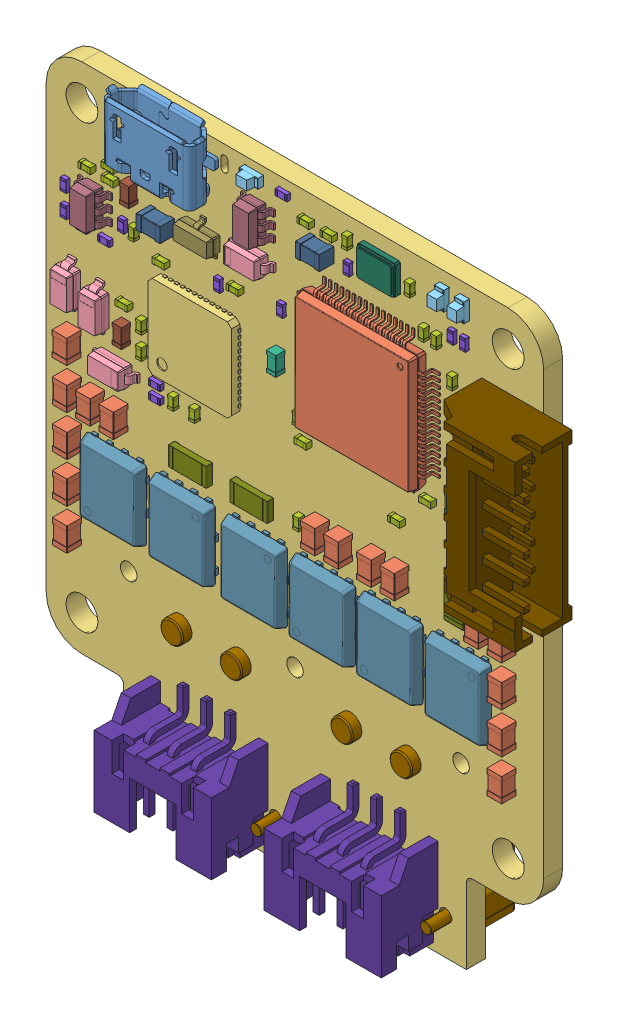
SolidWorks assembly Daedalus, configuration Default. Lengths in mm.
Overall size (44.43 51.31 11.63).
180 component instances, 21 part files, 0 mates.
Components (placement in the parent):
- Daedalus.step-1: Daedalus.step [Default] at origin size (44.43 51.31 11.63)
  - molex_0473460001.step-1: molex_0473460001.step [Default] at (133.8224 -76.8655 1.65) x (-1 0 0) z (0 1 0) size (7.98 2.76 5.43)
    - COMPOUND.step-1: COMPOUND.step [Default] at origin size (7.98 2.76 5.43)
  - LQFP-64_10x10mm_P0.5mm.step-1: LQFP-64_10x10mm_P0.5mm.step [Default] at (150.2843 -86.8057 1.65) x (0 -1 0) z (0 0 1) size (12 12 1.5)
    - SOLID.step-1: SOLID.step [Default] at origin size (12 12 1.5)
  - QFN127P600-8N.step-1: QFN127P600-8N.step [Default] at (135.871 -91.0039 1.65) x (0 1 0) z (0 0 1) size (7.15 7.15 0.75)
    - COMPOUND-0.step-1: COMPOUND-0.step [Default] at origin size (7.15 7.15 0.75)
  - D_SOD-123.step-1: D_SOD-123.step [Default] at (140.4976 -82.2096 1.65) size (3.8 1.6 1.25)
    - SOLID-1.step-1: SOLID-1.step [Default] at origin size (3.8 1.6 1.25)
  - LED_0603_1608Metric.step-1: LED_0603_1608Metric.step [Default] at (156.6516 -77.1197 1.65) x (0 1 0) z (0 0 1) size (1.6 0.8 1.1)
    - SOLID-2.step-1: SOLID-2.step [Default] at origin size (1.6 0.8 1.1)
  - C_0603_1608Metric.step-1: C_0603_1608Metric.step [Default] at (157.7975 -91.44 1.65) x (0 -1 0) z (0 0 1) size (1.6 0.8 0.8)
    - SOLID-3.step-1: SOLID-3.step [Default] at origin size (1.6 0.8 0.8)
  - C_0402_1005Metric.step-1: C_0402_1005Metric.step [Default] at (130.6322 -85.3769 1.65) x (0 -1 0) z (0 0 1) size (1 0.5 0.5)
    - SOLID-4.step-1: SOLID-4.step [Default] at origin size (1 0.5 0.5)
  - C_0402_1005Metric.step-2: C_0402_1005Metric.step [Default] at (126.6952 -82.5398 1.65) x (-1 0 0) z (0 0 1) size (1 0.5 0.5)
    - SOLID-4.step-1: SOLID-4.step [Default] at origin size (1 0.5 0.5)
  - R_0402_1005Metric.step-1: R_0402_1005Metric.step [Default] at (143.0426 -84.8411 1.65) x (0 -1 0) z (0 0 1) size (1 0.5 0.35)
    - SOLID-5.step-1: SOLID-5.step [Default] at origin size (1 0.5 0.35)
  - C_0402_1005Metric.step-3: C_0402_1005Metric.step [Default] at (147.0948 -77.337 1.65) size (1 0.5 0.5)
    - SOLID-4.step-1: SOLID-4.step [Default] at origin size (1 0.5 0.5)
  - Amass_XT30PW-M_pcb_solder.step-1: Amass_XT30PW-M_pcb_solder.step [Default] at (151.1541 -116.5924 -2.59) x (-1 0 0) z (0 0 -1) size (13.3 13.95 8.49)
    - SOLID-6.step-1: SOLID-6.step [Default] at origin size (13.3 13.95 8.49)
  - Amass_XT30PW-M_pcb_solder.step-2: Amass_XT30PW-M_pcb_solder.step [Default] at (136.8031 -116.5924 -2.59) x (-1 0 0) z (0 0 -1) size (13.3 13.95 8.49)
    - SOLID-6.step-1: SOLID-6.step [Default] at origin size (13.3 13.95 8.49)
  - R_0402_1005Metric.step-2: R_0402_1005Metric.step [Default] at (132.4508 -96.6368 1.65) x (-1 0 0) z (0 0 1) size (1 0.5 0.35)
    - SOLID-5.step-1: SOLID-5.step [Default] at origin size (1 0.5 0.35)
  - C_0402_1005Metric.step-4: C_0402_1005Metric.step [Default] at (128.6307 -82.55 1.65) size (1 0.5 0.5)
    - SOLID-4.step-1: SOLID-4.step [Default] at origin size (1 0.5 0.5)
  - C_0402_1005Metric.step-5: C_0402_1005Metric.step [Default] at (128.6307 -81.5442 1.65) size (1 0.5 0.5)
    - SOLID-4.step-1: SOLID-4.step [Default] at origin size (1 0.5 0.5)
  - C_0402_1005Metric.step-6: C_0402_1005Metric.step [Default] at (156.1898 -80.4962 1.65) x (0 -1 0) z (0 0 1) size (1 0.5 0.5)
    - SOLID-4.step-1: SOLID-4.step [Default] at origin size (1 0.5 0.5)
  - C_0402_1005Metric.step-7: C_0402_1005Metric.step [Default] at (157.5233 -82.8282 1.65) x (0 1 0) z (0 0 1) size (1 0.5 0.5)
    - SOLID-4.step-1: SOLID-4.step [Default] at origin size (1 0.5 0.5)
  - C_0402_1005Metric.step-8: C_0402_1005Metric.step [Default] at (144.9198 -93.5904 1.65) size (1 0.5 0.5)
    - SOLID-4.step-1: SOLID-4.step [Default] at origin size (1 0.5 0.5)
  - C_0402_1005Metric.step-9: C_0402_1005Metric.step [Default] at (144.5058 -91.9897 1.65) x (0 1 0) z (0 0 1) size (1 0.5 0.5)
    - SOLID-4.step-1: SOLID-4.step [Default] at origin size (1 0.5 0.5)
  - C_0402_1005Metric.step-10: C_0402_1005Metric.step [Default] at (155.1103 -80.4787 1.65) x (0 -1 0) z (0 0 1) size (1 0.5 0.5)
    - SOLID-4.step-1: SOLID-4.step [Default] at origin size (1 0.5 0.5)
  - C_0402_1005Metric.step-11: C_0402_1005Metric.step [Default] at (155.4448 -92.6154 1.65) x (-1 0 0) z (0 0 1) size (1 0.5 0.5)
    - SOLID-4.step-1: SOLID-4.step [Default] at origin size (1 0.5 0.5)
  - C_0402_1005Metric.step-12: C_0402_1005Metric.step [Default] at (145.1598 -77.337 1.65) size (1 0.5 0.5)
    - SOLID-4.step-1: SOLID-4.step [Default] at origin size (1 0.5 0.5)
  - C_0402_1005Metric.step-13: C_0402_1005Metric.step [Default] at (131.2824 -93.787 1.65) x (0 1 0) z (0 0 1) size (1 0.5 0.5)
    - SOLID-4.step-1: SOLID-4.step [Default] at origin size (1 0.5 0.5)
  - C_0402_1005Metric.step-14: C_0402_1005Metric.step [Default] at (133.9799 -96.078 1.65) x (0 1 0) z (0 0 1) size (1 0.5 0.5)
    - SOLID-4.step-1: SOLID-4.step [Default] at origin size (1 0.5 0.5)
  - C_0402_1005Metric.step-15: C_0402_1005Metric.step [Default] at (132.9334 -86.4108 1.65) x (-1 0 0) z (0 0 1) size (1 0.5 0.5)
    - SOLID-4.step-1: SOLID-4.step [Default] at origin size (1 0.5 0.5)
  - C_0402_1005Metric.step-16: C_0402_1005Metric.step [Default] at (131.2824 -91.8566 1.65) x (0 -1 0) z (0 0 1) size (1 0.5 0.5)
    - SOLID-4.step-1: SOLID-4.step [Default] at origin size (1 0.5 0.5)
  - C_0603_1608Metric.step-2: C_0603_1608Metric.step [Default] at (142.7886 -88.6663 1.65) x (0 1 0) z (0 0 1) size (1.6 0.8 0.8)
    - SOLID-3.step-1: SOLID-3.step [Default] at origin size (1.6 0.8 0.8)
  - C_0402_1005Metric.step-17: C_0402_1005Metric.step [Default] at (135.7681 -96.0703 1.65) x (0 -1 0) z (0 0 1) size (1 0.5 0.5)
    - SOLID-4.step-1: SOLID-4.step [Default] at origin size (1 0.5 0.5)
  - C_0402_1005Metric.step-18: C_0402_1005Metric.step [Default] at (129.8042 -91.059 1.65) size (1 0.5 0.5)
    - SOLID-4.step-1: SOLID-4.step [Default] at origin size (1 0.5 0.5)
  - C_0402_1005Metric.step-19: C_0402_1005Metric.step [Default] at (153.9443 -77.8002 1.65) x (0 1 0) z (0 0 1) size (1 0.5 0.5)
    - SOLID-4.step-1: SOLID-4.step [Default] at origin size (1 0.5 0.5)
  - C_0402_1005Metric.step-20: C_0402_1005Metric.step [Default] at (148.6511 -76.9989 1.65) x (0 -1 0) z (0 0 1) size (1 0.5 0.5)
    - SOLID-4.step-1: SOLID-4.step [Default] at origin size (1 0.5 0.5)
  - C_0402_1005Metric.step-21: C_0402_1005Metric.step [Default] at (139.1944 -85.2119 1.65) size (1 0.5 0.5)
    - SOLID-4.step-1: SOLID-4.step [Default] at origin size (1 0.5 0.5)
  - D_SOD-123.step-2: D_SOD-123.step [Default] at (127.6502 -92.3595 1.65) x (0 -1 0) z (0 0 1) size (3.8 1.6 1.25)
    - SOLID-1.step-1: SOLID-1.step [Default] at origin size (3.8 1.6 1.25)
  - D_SOD-123.step-3: D_SOD-123.step [Default] at (125.2677 -91.8616 1.65) x (0 -1 0) z (0 0 1) size (3.8 1.6 1.25)
    - SOLID-1.step-1: SOLID-1.step [Default] at origin size (3.8 1.6 1.25)
  - D_SOD-123.step-4: D_SOD-123.step [Default] at (129.0218 -96.0222 1.65) x (-1 0 0) z (0 0 1) size (3.8 1.6 1.25)
    - SOLID-1.step-1: SOLID-1.step [Default] at origin size (3.8 1.6 1.25)
  - LED_0603_1608Metric.step-2: LED_0603_1608Metric.step [Default] at (158.3516 -77.1197 1.65) x (0 1 0) z (0 0 1) size (1.6 0.8 1.1)
    - SOLID-2.step-1: SOLID-2.step [Default] at origin size (1.6 0.8 1.1)
  - L_0805_2012Metric.step-1: L_0805_2012Metric.step [Default] at (132.8369 -83.5203 1.65) size (2 1.25 1.25)
    - SOLID-7.step-1: SOLID-7.step [Default] at origin size (2 1.25 1.25)
  - L_0805_2012Metric.step-2: L_0805_2012Metric.step [Default] at (146.2948 -78.837 1.65) x (-1 0 0) z (0 0 1) size (2 1.25 1.25)
    - SOLID-7.step-1: SOLID-7.step [Default] at origin size (2 1.25 1.25)
  - L_0603_1608Metric.step-1: L_0603_1608Metric.step [Default] at (130.3579 -82.5449 1.65) x (0 1 0) z (0 0 1) size (1.6 0.8 0.8)
    - SOLID-8.step-1: SOLID-8.step [Default] at origin size (1.6 0.8 0.8)
  - L_0603_1608Metric.step-2: L_0603_1608Metric.step [Default] at (129.7483 -93.152 1.65) x (0 1 0) z (0 0 1) size (1.6 0.8 0.8)
    - SOLID-8.step-1: SOLID-8.step [Default] at origin size (1.6 0.8 0.8)
  - SOT-23.step-1: SOT-23.step [Default] at (136.3269 -82.7481 1.65) x (0 1 0) z (0 0 1) size (2.5 3 1.2)
    - SOLID-9.step-1: SOLID-9.step [Default] at origin size (2.5 3 1.2)
  - R_0402_1005Metric.step-3: R_0402_1005Metric.step [Default] at (124.7699 -84.8411 1.65) x (0 -1 0) z (0 0 1) size (1 0.5 0.35)
    - SOLID-5.step-1: SOLID-5.step [Default] at origin size (1 0.5 0.35)
  - R_0402_1005Metric.step-4: R_0402_1005Metric.step [Default] at (129.6314 -85.3796 1.65) x (0 -1 0) z (0 0 1) size (1 0.5 0.35)
    - SOLID-5.step-1: SOLID-5.step [Default] at origin size (1 0.5 0.35)
  - R_0402_1005Metric.step-5: R_0402_1005Metric.step [Default] at (126.2356 -87.2134 1.65) x (-1 0 0) z (0 0 1) size (1 0.5 0.35)
    - SOLID-5.step-1: SOLID-5.step [Default] at origin size (1 0.5 0.35)
  - R_0402_1005Metric.step-6: R_0402_1005Metric.step [Default] at (128.1762 -87.2134 1.65) x (-1 0 0) z (0 0 1) size (1 0.5 0.35)
    - SOLID-5.step-1: SOLID-5.step [Default] at origin size (1 0.5 0.35)
  - R_0402_1005Metric.step-7: R_0402_1005Metric.step [Default] at (124.7699 -86.7586 1.65) x (0 1 0) z (0 0 1) size (1 0.5 0.35)
    - SOLID-5.step-1: SOLID-5.step [Default] at origin size (1 0.5 0.35)
  - R_0402_1005Metric.step-8: R_0402_1005Metric.step [Default] at (137.7239 -85.6691 1.65) x (0 -1 0) z (0 0 1) size (1 0.5 0.35)
    - SOLID-5.step-1: SOLID-5.step [Default] at origin size (1 0.5 0.35)
  - R_0402_1005Metric.step-9: R_0402_1005Metric.step [Default] at (148.6511 -79.0079 1.65) x (0 1 0) z (0 0 1) size (1 0.5 0.35)
    - SOLID-5.step-1: SOLID-5.step [Default] at origin size (1 0.5 0.35)
  - R_0402_1005Metric.step-10: R_0402_1005Metric.step [Default] at (132.4508 -95.6158 1.65) size (1 0.5 0.35)
    - SOLID-5.step-1: SOLID-5.step [Default] at origin size (1 0.5 0.35)
  - R_0402_1005Metric.step-11: R_0402_1005Metric.step [Default] at (157.9931 -84.3178 1.65) x (-1 0 0) z (0 0 1) size (1 0.5 0.35)
    - SOLID-5.step-1: SOLID-5.step [Default] at origin size (1 0.5 0.35)
  - R_0402_1005Metric.step-12: R_0402_1005Metric.step [Default] at (157.4546 -79.6036 1.65) x (0 1 0) z (0 0 1) size (1 0.5 0.35)
    - SOLID-5.step-1: SOLID-5.step [Default] at origin size (1 0.5 0.35)
  - R_0402_1005Metric.step-13: R_0402_1005Metric.step [Default] at (158.4757 -79.6036 1.65) x (0 1 0) z (0 0 1) size (1 0.5 0.35)
    - SOLID-5.step-1: SOLID-5.step [Default] at origin size (1 0.5 0.35)
  - SOT-23-6.step-1: SOT-23-6.step [Default] at (127.2032 -84.8766 1.65) size (2.8 2.9 1.55)
    - SOLID-10.step-1: SOLID-10.step [Default] at origin size (2.8 2.9 1.55)
  - PowerFLAT_5x6.step-1: PowerFLAT_5x6.step [Default] at (129.1488 -104.9142 1.65) size (5.2 6.19 1.01)
    - COMPOUND-11.step-1: COMPOUND-11.step [Default] at origin size (5.2 6.19 1.01)
  - PowerFLAT_5x6.step-2: PowerFLAT_5x6.step [Default] at (146.8018 -104.9071 1.65) size (5.2 6.19 1.01)
    - COMPOUND-11.step-1: COMPOUND-11.step [Default] at origin size (5.2 6.19 1.01)
  - PowerFLAT_5x6.step-3: PowerFLAT_5x6.step [Default] at (152.5041 -104.8507 1.65) size (5.2 6.19 1.01)
    - COMPOUND-11.step-1: COMPOUND-11.step [Default] at origin size (5.2 6.19 1.01)
  - PowerFLAT_5x6.step-4: PowerFLAT_5x6.step [Default] at (134.9908 -104.9071 1.65) x (-1 0 0) z (0 0 1) size (5.2 6.19 1.01)
    - COMPOUND-11.step-1: COMPOUND-11.step [Default] at origin size (5.2 6.19 1.01)
  - PowerFLAT_5x6.step-5: PowerFLAT_5x6.step [Default] at (141.0868 -104.9127 1.65) x (-1 0 0) z (0 0 1) size (5.2 6.19 1.01)
    - COMPOUND-11.step-1: COMPOUND-11.step [Default] at origin size (5.2 6.19 1.01)
  - PowerFLAT_5x6.step-6: PowerFLAT_5x6.step [Default] at (158.308 -104.8619 1.65) x (-1 0 0) z (0 0 1) size (5.2 6.19 1.01)
    - COMPOUND-11.step-1: COMPOUND-11.step [Default] at origin size (5.2 6.19 1.01)
  - SOT-23-6.step-2: SOT-23-6.step [Default] at (140.9598 -79.1972 1.65) size (2.8 2.9 1.55)
    - SOLID-10.step-1: SOLID-10.step [Default] at origin size (2.8 2.9 1.55)
  - Crystal_SMD_3225-4Pin_3.2x2.5mm.step-1: Crystal_SMD_3225-4Pin_3.2x2.5mm.step [Default] at (151.3003 -77.7658 1.65) x (-1 0 0) z (0 0 1) size (3.2 2.5 0.64)
    - SOLID-12.step-1: SOLID-12.step [Default] at origin size (3.2 2.5 0.64)
  - R_1206_3216Metric.step-1: R_1206_3216Metric.step [Default] at (135.4607 -99.9668 1.65) size (3.2 1.6 0.55)
    - SOLID-13.step-1: SOLID-13.step [Default] at origin size (3.2 1.6 0.55)
  - R_1206_3216Metric.step-2: R_1206_3216Metric.step [Default] at (140.6169 -99.9668 1.65) x (-1 0 0) z (0 0 1) size (3.2 1.6 0.55)
    - SOLID-13.step-1: SOLID-13.step [Default] at origin size (3.2 1.6 0.55)
  - R_1206_3216Metric.step-3: R_1206_3216Metric.step [Default] at (157.9524 -98.7476 1.65) x (0 1 0) z (0 0 1) size (3.2 1.6 0.55)
    - SOLID-13.step-1: SOLID-13.step [Default] at origin size (3.2 1.6 0.55)
  - S3B-PH-SM4-TB.step-1: S3B-PH-SM4-TB.step [Default] at (151.1414 -124.9236 1.65) x (1 0 0) z (0 -1 0) size (9.9 4.8 8.6)
    - COMPOUND-14.step-1: COMPOUND-14.step [Default] at origin size (9.9 4.8 8.6)
  - S3B-PH-SM4-TB.step-2: S3B-PH-SM4-TB.step [Default] at (136.7904 -124.9288 1.65) x (1 0 0) z (0 -1 0) size (9.9 4.8 8.6)
    - COMPOUND-14.step-1: COMPOUND-14.step [Default] at origin size (9.9 4.8 8.6)
  - JST_PH_S6B-PH-K_1x06_P2.00mm_Horizontal.step-1: JST_PH_S6B-PH-K_1x06_P2.00mm_Horizontal.step [Default] at (161.1274 -93.538 1.65) x (0 1 0) z (0 0 1) size (13.9 7.6 8.25)
    - SOLID-15.step-1: SOLID-15.step [Default] at origin size (13.9 7.6 8.25)
  - TSSOP-14.step-1: TSSOP-14.step [Default] at (143.9164 -93.7666 -0.05) x (0 1 0) z (0 0 -1) size (6.43 7.25 1.1)
    - COMPOUND-16.step-1: COMPOUND-16.step [Default] at origin size (6.43 7.25 1.1)
  - C_0805_2012Metric.step-1: C_0805_2012Metric.step [Default] at (151.0563 -99.3572 1.65) x (0 1 0) z (0 0 1) size (2 1.25 1.25)
    - SOLID-17.step-1: SOLID-17.step [Default] at origin size (2 1.25 1.25)
  - C_0805_2012Metric.step-2: C_0805_2012Metric.step [Default] at (162.0799 -99.3676 1.65) x (0 1 0) z (0 0 1) size (2 1.25 1.25)
    - SOLID-17.step-1: SOLID-17.step [Default] at origin size (2 1.25 1.25)
  - C_0805_2012Metric.step-3: C_0805_2012Metric.step [Default] at (125.349 -95.9838 1.65) x (0 -1 0) z (0 0 1) size (2 1.25 1.25)
    - SOLID-17.step-1: SOLID-17.step [Default] at origin size (2 1.25 1.25)
  - C_0805_2012Metric.step-4: C_0805_2012Metric.step [Default] at (162.0774 -109.6721 1.65) x (0 1 0) z (0 0 1) size (2 1.25 1.25)
    - SOLID-17.step-1: SOLID-17.step [Default] at origin size (2 1.25 1.25)
  - C_0805_2012Metric.step-5: C_0805_2012Metric.step [Default] at (160.0987 -99.3595 1.65) x (0 1 0) z (0 0 1) size (2 1.25 1.25)
    - SOLID-17.step-1: SOLID-17.step [Default] at origin size (2 1.25 1.25)
  - C_0805_2012Metric.step-6: C_0805_2012Metric.step [Default] at (125.3769 -106.2637 1.65) x (0 1 0) z (0 0 1) size (2 1.25 1.25)
    - SOLID-17.step-1: SOLID-17.step [Default] at origin size (2 1.25 1.25)
  - C_0805_2012Metric.step-7: C_0805_2012Metric.step [Default] at (153.0248 -99.3549 1.65) x (0 1 0) z (0 0 1) size (2 1.25 1.25)
    - SOLID-17.step-1: SOLID-17.step [Default] at origin size (2 1.25 1.25)
  - C_0805_2012Metric.step-8: C_0805_2012Metric.step [Default] at (129.2962 -99.4207 1.65) x (0 1 0) z (0 0 1) size (2 1.25 1.25)
    - SOLID-17.step-1: SOLID-17.step [Default] at origin size (2 1.25 1.25)
  - C_0805_2012Metric.step-9: C_0805_2012Metric.step [Default] at (125.3769 -102.8474 1.65) x (0 -1 0) z (0 0 1) size (2 1.25 1.25)
    - SOLID-17.step-1: SOLID-17.step [Default] at origin size (2 1.25 1.25)
  - C_0805_2012Metric.step-10: C_0805_2012Metric.step [Default] at (146.3065 -99.4207 1.65) x (0 1 0) z (0 0 1) size (2 1.25 1.25)
    - SOLID-17.step-1: SOLID-17.step [Default] at origin size (2 1.25 1.25)
  - C_0805_2012Metric.step-11: C_0805_2012Metric.step [Default] at (162.0799 -106.2383 1.65) x (0 1 0) z (0 0 1) size (2 1.25 1.25)
    - SOLID-17.step-1: SOLID-17.step [Default] at origin size (2 1.25 1.25)
  - C_0805_2012Metric.step-12: C_0805_2012Metric.step [Default] at (125.3795 -109.6924 1.65) x (0 -1 0) z (0 0 1) size (2 1.25 1.25)
    - SOLID-17.step-1: SOLID-17.step [Default] at origin size (2 1.25 1.25)
  - C_0805_2012Metric.step-13: C_0805_2012Metric.step [Default] at (127.3277 -99.4207 1.65) x (0 1 0) z (0 0 1) size (2 1.25 1.25)
    - SOLID-17.step-1: SOLID-17.step [Default] at origin size (2 1.25 1.25)
  - C_0805_2012Metric.step-14: C_0805_2012Metric.step [Default] at (162.0799 -102.7989 1.65) x (0 -1 0) z (0 0 1) size (2 1.25 1.25)
    - SOLID-17.step-1: SOLID-17.step [Default] at origin size (2 1.25 1.25)
  - C_0805_2012Metric.step-15: C_0805_2012Metric.step [Default] at (125.3592 -99.4207 1.65) x (0 1 0) z (0 0 1) size (2 1.25 1.25)
    - SOLID-17.step-1: SOLID-17.step [Default] at origin size (2 1.25 1.25)
  - C_0805_2012Metric.step-16: C_0805_2012Metric.step [Default] at (148.275 -99.4207 1.65) x (0 1 0) z (0 0 1) size (2 1.25 1.25)
    - SOLID-17.step-1: SOLID-17.step [Default] at origin size (2 1.25 1.25)
  - LED_0603_1608Metric.step-3: LED_0603_1608Metric.step [Default] at (140.5738 -76.3676 1.65) x (-1 0 0) z (0 0 1) size (1.6 0.8 1.1)
    - SOLID-2.step-1: SOLID-2.step [Default] at origin size (1.6 0.8 1.1)
  - R_0402_1005Metric.step-14: R_0402_1005Metric.step [Default] at (143.1646 -76.3676 1.65) x (-1 0 0) z (0 0 1) size (1 0.5 0.35)
    - SOLID-5.step-1: SOLID-5.step [Default] at origin size (1 0.5 0.35)
  - C_0402_1005Metric.step-22: C_0402_1005Metric.step [Default] at (144.5514 -99.606 1.65) x (0 -1 0) z (0 0 1) size (1 0.5 0.5)
    - SOLID-4.step-1: SOLID-4.step [Default] at origin size (1 0.5 0.5)
  - C_0402_1005Metric.step-23: C_0402_1005Metric.step [Default] at (152.8317 -95.3389 1.65) x (-1 0 0) z (0 0 1) size (1 0.5 0.5)
    - SOLID-4.step-1: SOLID-4.step [Default] at origin size (1 0.5 0.5)
  - C_0402_1005Metric.step-24: C_0402_1005Metric.step [Default] at (160.6297 -96.8883 1.65) size (1 0.5 0.5)
    - SOLID-4.step-1: SOLID-4.step [Default] at origin size (1 0.5 0.5)
  - COMPOUND-18.step-1: COMPOUND-18.step [Default] at origin size (42.01 50.16 1.6)
